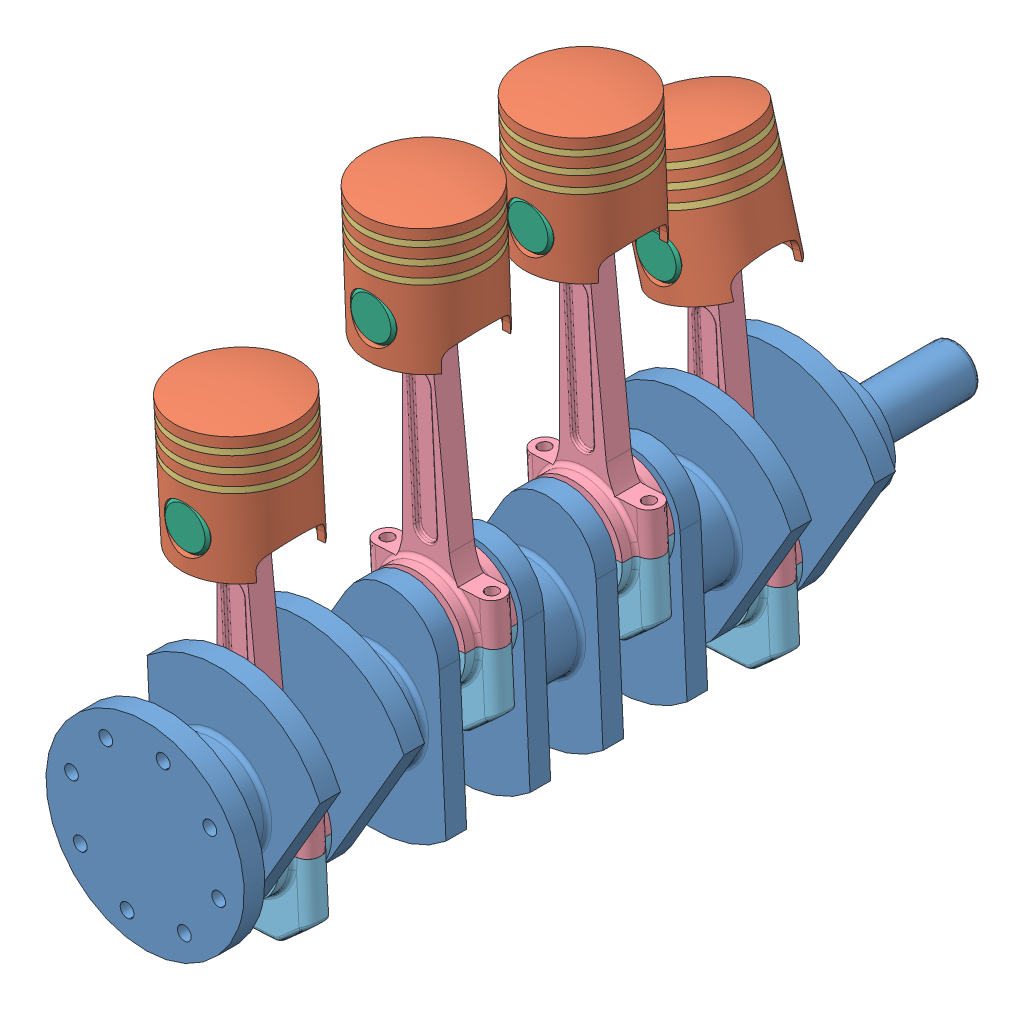
SolidWorks assembly Assem, configuration Default. Lengths in mm.
Overall size (177.95 418.46 589).
29 component instances, 6 part files, 66 mates.
Components (placement in the parent):
- Part3 crankshaft-1: Part3 crankshaft [Default] at (0 0 -456) x (0.971241 -0.238097 0) z (0 0 1) size (144 160 589)
- Part1.pistonSLDPRT-1: Part1.pistonSLDPRT [Default] at (-13.8266 132.1617 -433) x (0.963997 0.265913 0) z (0 0 1) size (85 95 85)
- Part2 piston ring -1: Part2 piston ring  [Default] at (-34.6742 207.7391 -433) x (0.922759 0.254538 0.289354) z (-0.278936 -0.076943 0.957222) size (85 4.3 85)
- Part4 Connecting rods-1: Part4 Connecting rods [Default] at (-21.0063 158.1896 -433) x (0.99863 0.052336 0) z (0 0 1) size (94 223.7 38)
- Part5 connecting rod cap-1: Part5 connecting rod cap [Default] at (-10.4763 -42.7346 -433) x (-0.99863 -0.052336 0) z (0 0 1) size (94 60 38)
- Part2 piston ring -15: Part2 piston ring  [Default] at (-31.5896 196.5567 -433) x (0.939398 0.259128 0.224464) z (-0.216383 -0.059688 0.974482) size (85 4.3 85)
- Part2 piston ring -18: Part2 piston ring  [Default] at (-28.505 185.3744 -433) x (0.961744 0.265292 0.068331) z (-0.065871 -0.01817 0.997663) size (85 4.3 85)
- Part6 pinston pin -4: Part6 pinston pin  [Default] at (-21.0063 158.1896 -433) x (0.997486 0.070858 0) z (0 0 1) size (33 33 82)
- Part2 piston ring -20: Part2 piston ring  [Default] at (-2.1541 295.016 -319) x (0.992639 0.040597 0.114108) z (-0.114013 -0.004663 0.993468) size (85 4.3 85)
- Part2 piston ring -21: Part2 piston ring  [Default] at (-1.6801 283.4256 -319) x (0.998052 0.040818 0.047181) z (-0.047142 -0.001928 0.998886) size (85 4.3 85)
- Part1.pistonSLDPRT-2: Part1.pistonSLDPRT [Default] at (1.0496 216.6814 -319) x (0.999165 0.040864 0) z (0 0 1) size (85 95 85)
- Part2 piston ring -22: Part2 piston ring  [Default] at (-1.2061 271.8353 -319) x (0.995496 0.040714 -0.085616) z (0.085545 0.003499 0.996328) size (85 4.3 85)
- Part6 pinston pin -5: Part6 pinston pin  [Default] at (-0.0537 243.6589 -319) x (0.973634 0.228116 0) z (0 0 1) size (33 33 82)
- Part4 Connecting rods-2: Part4 Connecting rods [Default] at (-0.0537 243.6589 -319) x (0.99863 0.052336 0) z (0 0 1) size (94 223.7 38)
- Part5 connecting rod cap-2: Part5 connecting rod cap [Default] at (10.4763 42.7346 -319) x (-0.99863 -0.052336 0) z (0 0 1) size (94 60 38)
- Part5 connecting rod cap-7: Part5 connecting rod cap [Default] at (10.4763 42.7346 -205) x (-0.99863 -0.052336 0) z (0 0 1) size (94 60 38)
- Part4 Connecting rods-7: Part4 Connecting rods [Default] at (-0.0537 243.6589 -205) x (0.99863 0.052336 0) z (0 0 1) size (94 223.7 38)
- Part1.pistonSLDPRT-7: Part1.pistonSLDPRT [Default] at (1.059 216.6818 -205) x (0.99915 0.041212 0) z (0 0 1) size (85 95 85)
- Part6 pinston pin -10: Part6 pinston pin  [Default] at (-0.0537 243.6589 -205) x (0.973634 0.228116 0) z (0 0 1) size (33 33 82)
- Part2 piston ring -35: Part2 piston ring  [Default] at (-1.2159 271.8349 -205) x (0.995482 0.04106 -0.085616) z (0.085544 0.003528 0.996328) size (85 4.3 85)
- Part2 piston ring -36: Part2 piston ring  [Default] at (-1.6939 283.4251 -205) x (0.998038 0.041166 0.047181) z (-0.047141 -0.001944 0.998886) size (85 4.3 85)
- Part2 piston ring -37: Part2 piston ring  [Default] at (-2.172 295.0152 -205) x (0.992624 0.040942 0.114108) z (-0.114011 -0.004703 0.993468) size (85 4.3 85)
- Part5 connecting rod cap-9: Part5 connecting rod cap [Default] at (-10.4763 -42.7346 -91) x (-0.99863 -0.052336 0) z (0 0 1) size (94 60 38)
- Part4 Connecting rods-9: Part4 Connecting rods [Default] at (-21.0063 158.1896 -91) x (0.99863 0.052336 0) z (0 0 1) size (94 223.7 38)
- Part1.pistonSLDPRT-9: Part1.pistonSLDPRT [Default] at (-19.3491 131.2405 -91) x (0.998115 0.061378 0) z (0 0 1) size (85 95 85)
- Part6 pinston pin -12: Part6 pinston pin  [Default] at (-21.0063 158.1896 -91) x (0.936662 0.350234 0) z (0 0 1) size (33 33 82)
- Part2 piston ring -41: Part2 piston ring  [Default] at (-22.7371 186.3365 -91) x (0.961344 0.059117 -0.26893) z (0.268423 0.016506 0.96316) size (85 4.3 85)
- Part2 piston ring -42: Part2 piston ring  [Default] at (-23.4491 197.9146 -91) x (0.988438 0.060783 -0.138912) z (0.13865 0.008526 0.990305) size (85 4.3 85)
- Part2 piston ring -43: Part2 piston ring  [Default] at (-24.1611 209.4927 -91) x (0.995514 0.061218 -0.072141) z (0.072005 0.004428 0.997394) size (85 4.3 85)
Mates (geometry in assembly coordinates):
- Concentric6: concentric anti-aligned: cylinder of Part1.pistonSLDPRT-1 through (-31.5896 196.5567 -433) axis (-0.265913 0.963997 0) radius 39.5; cylinder of Part2 piston ring -15 through (-32.733 200.7019 -433) axis (0.265913 -0.963997 0) radius 42.5
- Coincident12: coincident anti-aligned: plane of Part1.pistonSLDPRT-1 through (-31.5896 196.5567 -433) normal (-0.265913 0.963997 0); plane of Part2 piston ring -15 through (-31.5896 196.5567 -433) normal (0.265913 -0.963997 0)
- Concentric32: concentric anti-aligned: cylinder of Part1.pistonSLDPRT-1 through (-28.505 185.3744 -433) axis (-0.265913 0.963997 0) radius 39.5; cylinder of Part2 piston ring -18 through (-29.6484 189.5195 -433) axis (0.265913 -0.963997 0) radius 42.5
- Coincident46: coincident anti-aligned: plane of Part1.pistonSLDPRT-1 through (-28.505 185.3744 -433) normal (-0.265913 0.963997 0); plane of Part2 piston ring -18 through (-28.505 185.3744 -433) normal (0.265913 -0.963997 0)
- Concentric33: concentric anti-aligned: circle of Part1.pistonSLDPRT-1; cylinder of Part2 piston ring -1 through (-35.8176 211.8843 -433) axis (0.265913 -0.963997 0) radius 42.5
- Coincident48: coincident anti-aligned: plane of Part1.pistonSLDPRT-1 through (-34.6742 207.7391 -433) normal (-0.265913 0.963997 0); plane of Part2 piston ring -1 through (-34.6742 207.7391 -433) normal (0.265913 -0.963997 0)
- Coincident49: coincident aligned: plane of Part1.pistonSLDPRT-1 through (-13.8266 132.1617 -433) normal (0 0 1); plane of Part4 Connecting rods-1 through (-21.0063 158.1896 -433) normal (0 0 1)
- Concentric36: concentric aligned: circle of Part4 Connecting rods-1; circle of Part5 connecting rod cap-1
- Concentric37: concentric aligned: circle of Part4 Connecting rods-1; cylinder of Part5 connecting rod cap-1 through (-45.284 -104.6412 -433) axis (-0.052336 0.99863 0) radius 4.5
- Coincident54: coincident anti-aligned: plane of Part4 Connecting rods-1 through (-10.4763 -42.7346 -414) normal (0.052336 -0.99863 0); plane of Part5 connecting rod cap-1 through (25.4744 -40.8505 -414) normal (-0.052336 0.99863 0)
- Width8: width anti-aligned: plane of Part3 crankshaft-1 through (0 0 -410) normal (0 0 -1); plane of Part3 crankshaft-1 through (0 0 -456) normal (0 0 1); plane of Part4 Connecting rods-1 through (-21.0063 158.1896 -424) normal (0 0 1); plane of Part4 Connecting rods-1 through (-21.0063 158.1896 -442) normal (0 0 -1)
- Concentric38: concentric aligned: cylinder of Part3 crankshaft-1 through (-10.4763 -42.7346 -410) axis (0 0 -1) radius 27; cylinder of Part5 connecting rod cap-1 through (-10.4763 -42.7346 -414) axis (0 0 -1) radius 27
- Concentric39: concentric anti-aligned: cylinder of Part3 crankshaft-1 through (0 0 -589) axis (0 0 1) radius 17.5
- Coincident56: coincident: plane of Part3 crankshaft-1 through (0 0 -589) normal (0 0 -1)
- Coincident57: coincident aligned: plane of Part1.pistonSLDPRT-1 through (-13.8266 132.1617 -433) normal (0 0 1); plane of Part6 pinston pin -4 through (-21.0063 158.1896 -433) normal (0 0 1)
- Concentric40: concentric anti-aligned: cylinder of Part1.pistonSLDPRT-1 through (-21.0063 158.1896 -475.5) axis (0 0 1) radius 16.9; cylinder of Part6 pinston pin -4 through (-21.0063 158.1896 -392) axis (0 0 -1) radius 16.5
- Concentric41: concentric aligned: cylinder of Part4 Connecting rods-1 through (-21.0063 158.1896 -414) axis (0 0 -1) radius 16.9; cylinder of Part6 pinston pin -4 through (-21.0063 158.1896 -392) axis (0 0 -1) radius 16.5
- Parallel5: parallel: plane of Part4 Connecting rods-1 through (-29.9377 158.1896 -424) normal (-1 0 0)
- Concentric42: concentric anti-aligned: cylinder of Part2 piston ring -21 through (-1.8558 287.722 -319) axis (0.040864 -0.999165 0) radius 42.5; cylinder of Part1.pistonSLDPRT-2 through (-1.6801 283.4256 -319) axis (-0.040864 0.999165 0) radius 39.5
- Coincident59: coincident anti-aligned: plane of Part2 piston ring -21 through (-1.6801 283.4256 -319) normal (0.040864 -0.999165 0); plane of Part1.pistonSLDPRT-2 through (-1.6801 283.4256 -319) normal (-0.040864 0.999165 0)
- Concentric43: concentric anti-aligned: cylinder of Part1.pistonSLDPRT-2 through (-1.2061 271.8353 -319) axis (-0.040864 0.999165 0) radius 39.5; cylinder of Part2 piston ring -22 through (-1.3818 276.1317 -319) axis (0.040864 -0.999165 0) radius 42.5
- Coincident60: coincident anti-aligned: plane of Part1.pistonSLDPRT-2 through (-1.2061 271.8353 -319) normal (-0.040864 0.999165 0); plane of Part2 piston ring -22 through (-1.2061 271.8353 -319) normal (0.040864 -0.999165 0)
- Concentric44: concentric anti-aligned: cylinder of Part2 piston ring -20 through (-2.3298 299.3124 -319) axis (0.040864 -0.999165 0) radius 42.5; circle of Part1.pistonSLDPRT-2
- Coincident61: coincident anti-aligned: plane of Part2 piston ring -20 through (-2.1541 295.016 -319) normal (0.040864 -0.999165 0); plane of Part1.pistonSLDPRT-2 through (-2.1541 295.016 -319) normal (-0.040864 0.999165 0)
- Coincident62: coincident aligned: plane of Part1.pistonSLDPRT-2 through (1.0496 216.6814 -319) normal (0 0 1); plane of Part4 Connecting rods-2 through (-0.0537 243.6589 -319) normal (0 0 1)
- Concentric45: concentric aligned: circle of Part4 Connecting rods-2; circle of Part5 connecting rod cap-2
- Concentric46: concentric aligned: circle of Part4 Connecting rods-2; cylinder of Part5 connecting rod cap-2 through (-24.3315 -19.1719 -319) axis (-0.052336 0.99863 0) radius 4.5
- Coincident63: coincident anti-aligned: plane of Part4 Connecting rods-2 through (10.4763 42.7346 -300) normal (0.052336 -0.99863 0); plane of Part5 connecting rod cap-2 through (46.4269 44.6187 -300) normal (-0.052336 0.99863 0)
- Coincident64: coincident aligned: plane of Part1.pistonSLDPRT-2 through (1.0496 216.6814 -319) normal (0 0 1); plane of Part6 pinston pin -5 through (-0.0537 243.6589 -319) normal (0 0 1)
- Concentric47: concentric anti-aligned: cylinder of Part1.pistonSLDPRT-2 through (-0.0537 243.6589 -361.5) axis (0 0 1) radius 16.9; cylinder of Part6 pinston pin -5 through (-0.0537 243.6589 -278) axis (0 0 -1) radius 16.5
- Concentric48: concentric aligned: cylinder of Part6 pinston pin -5 through (-0.0537 243.6589 -278) axis (0 0 -1) radius 16.5; cylinder of Part4 Connecting rods-2 through (-0.0537 243.6589 -300) axis (0 0 -1) radius 16.9
- Width9: width anti-aligned: plane of Part3 crankshaft-1 through (0 0 -342) normal (0 0 1); plane of Part3 crankshaft-1 through (0 0 -296) normal (0 0 -1); plane of Part4 Connecting rods-2 through (-0.0537 243.6589 -310) normal (0 0 1); plane of Part4 Connecting rods-2 through (-0.0537 243.6589 -328) normal (0 0 -1)
- Concentric49: concentric aligned: cylinder of Part3 crankshaft-1 through (10.4763 42.7346 -296) axis (0 0 -1) radius 27; cylinder of Part5 connecting rod cap-2 through (10.4763 42.7346 -300) axis (0 0 -1) radius 27
- Parallel6: parallel: plane of Part4 Connecting rods-2 through (-8.9852 243.6589 -310) normal (-1 0 0)
- Concentric80: concentric anti-aligned: cylinder of Part1.pistonSLDPRT-7 through (-1.6939 283.4251 -205) axis (-0.041212 0.99915 0) radius 39.5; cylinder of Part2 piston ring -36 through (-1.8712 287.7214 -205) axis (0.041212 -0.99915 0) radius 42.5
- Coincident89: coincident anti-aligned: plane of Part1.pistonSLDPRT-7 through (-1.6939 283.4251 -205) normal (-0.041212 0.99915 0); plane of Part2 piston ring -36 through (-1.6939 283.4251 -205) normal (0.041212 -0.99915 0)
- Concentric81: concentric anti-aligned: cylinder of Part1.pistonSLDPRT-7 through (-1.2159 271.8349 -205) axis (-0.041212 0.99915 0) radius 39.5; cylinder of Part2 piston ring -35 through (-1.3931 276.1313 -205) axis (0.041212 -0.99915 0) radius 42.5
- Coincident90: coincident anti-aligned: plane of Part1.pistonSLDPRT-7 through (-1.2159 271.8349 -205) normal (-0.041212 0.99915 0); plane of Part2 piston ring -35 through (-1.2159 271.8349 -205) normal (0.041212 -0.99915 0)
- Concentric82: concentric anti-aligned: circle of Part1.pistonSLDPRT-7; cylinder of Part2 piston ring -37 through (-2.3492 299.3116 -205) axis (0.041212 -0.99915 0) radius 42.5
- Coincident91: coincident anti-aligned: plane of Part1.pistonSLDPRT-7 through (-2.172 295.0152 -205) normal (-0.041212 0.99915 0); plane of Part2 piston ring -37 through (-2.172 295.0152 -205) normal (0.041212 -0.99915 0)
- Coincident92: coincident aligned: plane of Part4 Connecting rods-7 through (-0.0537 243.6589 -205) normal (0 0 1); plane of Part1.pistonSLDPRT-7 through (1.059 216.6818 -205) normal (0 0 1)
- Concentric83: concentric aligned: circle of Part5 connecting rod cap-7; circle of Part4 Connecting rods-7
- Concentric84: concentric aligned: cylinder of Part5 connecting rod cap-7 through (-24.3315 -19.1719 -205) axis (-0.052336 0.99863 0) radius 4.5; circle of Part4 Connecting rods-7
- Coincident93: coincident anti-aligned: plane of Part5 connecting rod cap-7 through (46.4269 44.6187 -186) normal (-0.052336 0.99863 0); plane of Part4 Connecting rods-7 through (10.4763 42.7346 -186) normal (0.052336 -0.99863 0)
- Coincident94: coincident aligned: plane of Part1.pistonSLDPRT-7 through (1.059 216.6818 -205) normal (0 0 1); plane of Part6 pinston pin -10 through (-0.0537 243.6589 -205) normal (0 0 1)
- Concentric85: concentric anti-aligned: cylinder of Part1.pistonSLDPRT-7 through (-0.0537 243.6589 -247.5) axis (0 0 1) radius 16.9; cylinder of Part6 pinston pin -10 through (-0.0537 243.6589 -164) axis (0 0 -1) radius 16.5
- Concentric86: concentric aligned: cylinder of Part4 Connecting rods-7 through (-0.0537 243.6589 -186) axis (0 0 -1) radius 16.9; cylinder of Part6 pinston pin -10 through (-0.0537 243.6589 -164) axis (0 0 -1) radius 16.5
- Width14: width anti-aligned: plane of Part3 crankshaft-1 through (0 0 -182) normal (0 0 -1); plane of Part3 crankshaft-1 through (0 0 -228) normal (0 0 1); plane of Part4 Connecting rods-7 through (-0.0537 243.6589 -196) normal (0 0 1); plane of Part4 Connecting rods-7 through (-0.0537 243.6589 -214) normal (0 0 -1)
- Concentric87: concentric anti-aligned: cylinder of Part3 crankshaft-1 through (10.4763 42.7346 -228) axis (0 0 1) radius 27; cylinder of Part5 connecting rod cap-7 through (10.4763 42.7346 -186) axis (0 0 -1) radius 27
- Parallel10: parallel: plane of Part4 Connecting rods-7 through (-8.9852 243.6589 -196) normal (-1 0 0)
- Concentric95: concentric anti-aligned: cylinder of Part1.pistonSLDPRT-9 through (-23.4491 197.9146 -91) axis (-0.061378 0.998115 0) radius 39.5; cylinder of Part2 piston ring -42 through (-23.713 202.2065 -91) axis (0.061378 -0.998115 0) radius 42.5
- Coincident101: coincident anti-aligned: plane of Part1.pistonSLDPRT-9 through (-23.4491 197.9146 -91) normal (-0.061378 0.998115 0); plane of Part2 piston ring -42 through (-23.4491 197.9146 -91) normal (0.061378 -0.998115 0)
- Concentric96: concentric anti-aligned: cylinder of Part1.pistonSLDPRT-9 through (-22.7371 186.3365 -91) axis (-0.061378 0.998115 0) radius 39.5; cylinder of Part2 piston ring -41 through (-23.001 190.6284 -91) axis (0.061378 -0.998115 0) radius 42.5
- Coincident102: coincident anti-aligned: plane of Part1.pistonSLDPRT-9 through (-22.7371 186.3365 -91) normal (-0.061378 0.998115 0); plane of Part2 piston ring -41 through (-22.7371 186.3365 -91) normal (0.061378 -0.998115 0)
- Concentric97: concentric anti-aligned: circle of Part1.pistonSLDPRT-9; cylinder of Part2 piston ring -43 through (-24.425 213.7846 -91) axis (0.061378 -0.998115 0) radius 42.5
- Coincident103: coincident anti-aligned: plane of Part1.pistonSLDPRT-9 through (-24.1611 209.4927 -91) normal (-0.061378 0.998115 0); plane of Part2 piston ring -43 through (-24.1611 209.4927 -91) normal (0.061378 -0.998115 0)
- Coincident104: coincident aligned: plane of Part4 Connecting rods-9 through (-21.0063 158.1896 -91) normal (0 0 1); plane of Part1.pistonSLDPRT-9 through (-19.3491 131.2405 -91) normal (0 0 1)
- Concentric98: concentric aligned: circle of Part5 connecting rod cap-9; circle of Part4 Connecting rods-9
- Concentric99: concentric aligned: cylinder of Part5 connecting rod cap-9 through (-45.284 -104.6412 -91) axis (-0.052336 0.99863 0) radius 4.5; circle of Part4 Connecting rods-9
- Coincident105: coincident anti-aligned: plane of Part5 connecting rod cap-9 through (25.4744 -40.8505 -72) normal (-0.052336 0.99863 0); plane of Part4 Connecting rods-9 through (-10.4763 -42.7346 -72) normal (0.052336 -0.99863 0)
- Coincident106: coincident aligned: plane of Part1.pistonSLDPRT-9 through (-19.3491 131.2405 -91) normal (0 0 1); plane of Part6 pinston pin -12 through (-21.0063 158.1896 -91) normal (0 0 1)
- Concentric100: concentric anti-aligned: cylinder of Part1.pistonSLDPRT-9 through (-21.0063 158.1896 -133.5) axis (0 0 1) radius 16.9; cylinder of Part6 pinston pin -12 through (-21.0063 158.1896 -50) axis (0 0 -1) radius 16.5
- Concentric101: concentric aligned: cylinder of Part4 Connecting rods-9 through (-21.0063 158.1896 -72) axis (0 0 -1) radius 16.9; cylinder of Part6 pinston pin -12 through (-21.0063 158.1896 -50) axis (0 0 -1) radius 16.5
- Width15: width anti-aligned: plane of Part3 crankshaft-1 through (0 0 -68) normal (0 0 -1); plane of Part3 crankshaft-1 through (0 0 -114) normal (0 0 1); plane of Part4 Connecting rods-9 through (-21.0063 158.1896 -82) normal (0 0 1); plane of Part4 Connecting rods-9 through (-21.0063 158.1896 -100) normal (0 0 -1)
- Concentric102: concentric anti-aligned: cylinder of Part3 crankshaft-1 through (-10.4763 -42.7346 -114) axis (0 0 1) radius 27; cylinder of Part5 connecting rod cap-9 through (-10.4763 -42.7346 -72) axis (0 0 -1) radius 27
- Parallel11: parallel: plane of Part4 Connecting rods-9 through (-29.9377 158.1896 -82) normal (-1 0 0)
